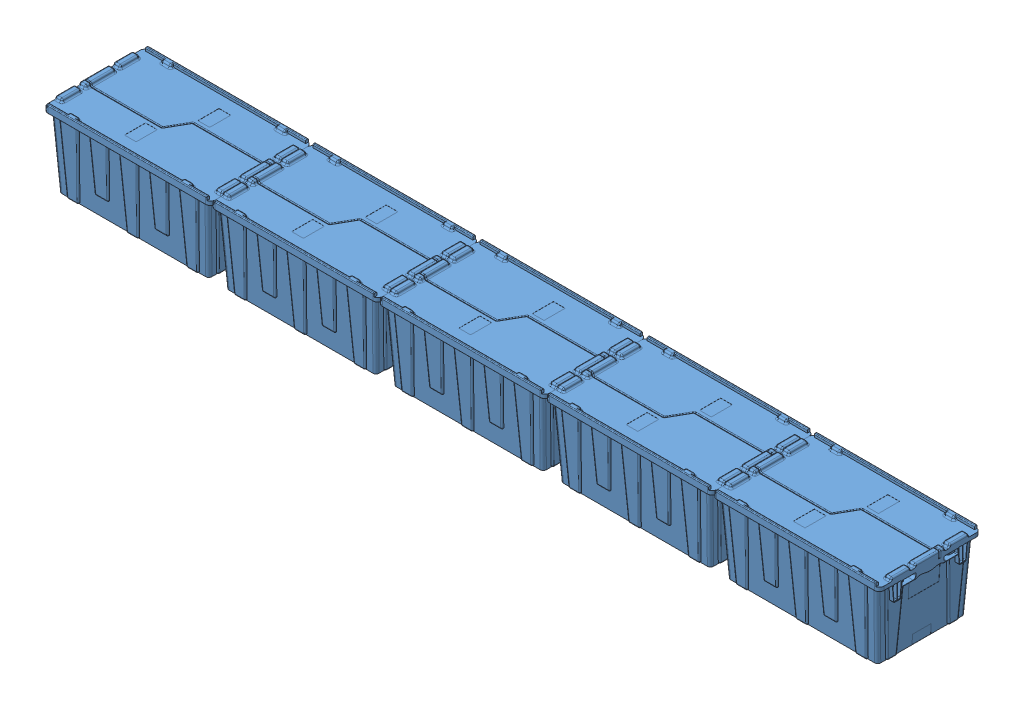
SolidWorks assembly LANDFILL_GP_ASM, configuration Default. Lengths in mm.
Overall size (3409.95 313.83 412.75).
5 component instances, 1 part files, 0 mates.
Components (placement in the parent):
- GRAY_TOTE-1: GRAY_TOTE [Default] at (-339.725 0 206.375) x (0 1 0) z (-1 0 0) size (313.83 412.75 692.15)
- GRAY_TOTE-2: GRAY_TOTE [Default] at (339.725 0 206.375) x (0 1 0) z (-1 0 0) size (313.83 412.75 692.15)
- GRAY_TOTE-3: GRAY_TOTE [Default] at (1019.175 0 206.375) x (0 1 0) z (-1 0 0) size (313.83 412.75 692.15)
- GRAY_TOTE-4: GRAY_TOTE [Default] at (1698.625 0 206.375) x (0 1 0) z (-1 0 0) size (313.83 412.75 692.15)
- GRAY_TOTE-5: GRAY_TOTE [Default] at (2378.075 0 206.375) x (0 1 0) z (-1 0 0) size (313.83 412.75 692.15)
